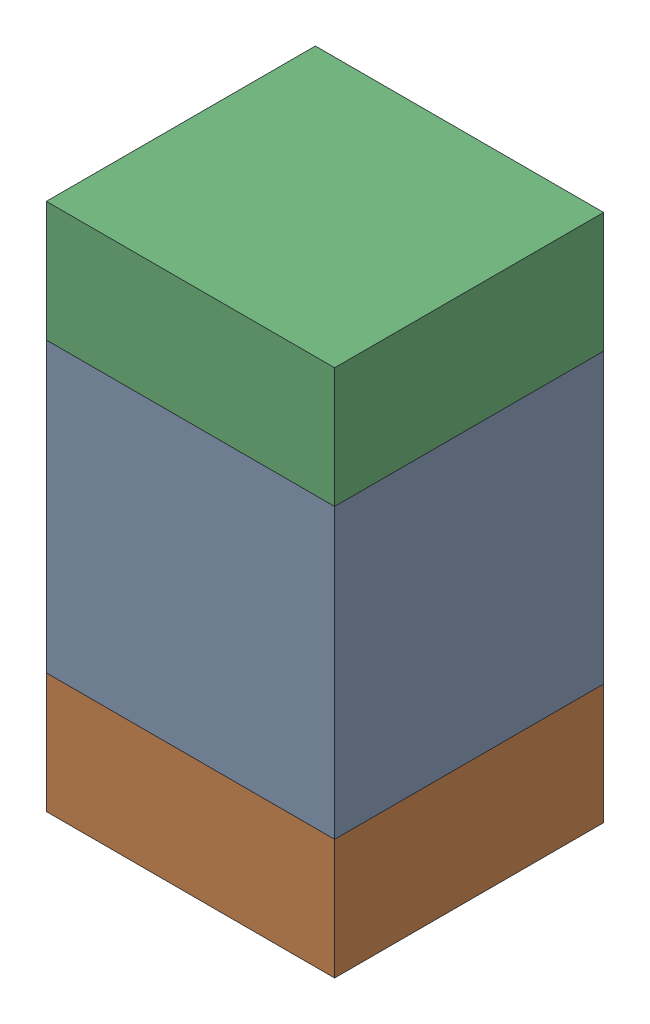
SolidWorks assembly C6, configuration Default. Lengths in mm.
Overall size (0.6 1.1 0.56).
6 component instances, 2 part files, 0 mates.
Components (placement in the parent):
- 5613967728-1: 5613967728 [Default] at (154 66.44 -2.2514) size (0.6 0.6 0.56)
  - Extruded-1: Extruded [Default] at origin size (0.6 0.6 0.56)
- 8144647408-1: 8144647408 [Default] at (154 66.015 -2.2514) size (0.6 0.25 0.56)
  - Extruded_7-1: Extruded_7 [Default] at origin size (0.6 0.25 0.56)
- 8144647408-2: 8144647408 [Default] at (154 66.865 -2.2514) size (0.6 0.25 0.56)
  - Extruded_7-1: Extruded_7 [Default] at origin size (0.6 0.25 0.56)
